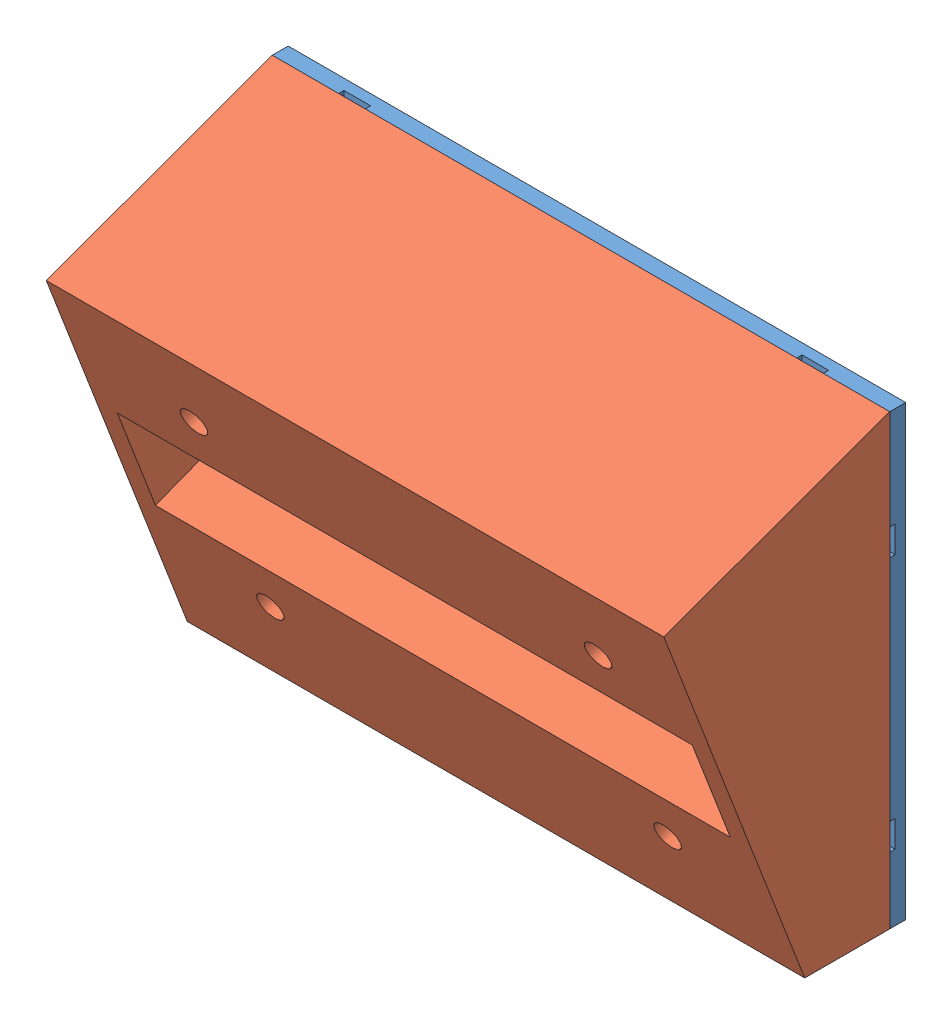
SolidWorks assembly front, configuration Default. Lengths in mm.
Overall size (116.2 84.29 45.53).
3 component instances, 3 part files, 8 mates.
Components (placement in the parent):
- LCD_mod-1: LCD_mod [Default] at (-40.4424 10.3291 10.6735) size (106.2 68 14) (hidden)
- front-case-1: front-case [Default] at (-40.4424 10.3291 7.3235) x (-1 0 0) z (0 0 -1) size (116.2 84.29 10)
- bottom-1: bottom [Default] at (-40.4424 10.3291 7.3235) size (116.2 84.29 42.53)
Mates (geometry in assembly coordinates):
- InPlace1: in place: plane of LCD_mod-1 through (-100.5567 53.2526 7.3235) normal (0 0 -1); plane of ? through (0 0 7.3235) normal (0 0 -1); moOrthogonalPlaneRef_w of LCD_mod-1 through (-100.5567 53.2526 7.3235) normal (0 0 -1); plane of ? through (0 0 7.3235) normal (0 1 0); plane of LCD_mod-1 through (-100.5567 53.2526 7.3235) normal (0 0 -1); plane of ? through (0 0 7.3235) normal (-1 0 0); plane of LCD_mod-1 through (-100.5567 53.2526 7.3235) normal (0 0 -1); unknown of front-case-1
- Coincident1: coincident aligned: plane of LCD_mod-1; plane of front-case-1
- Coincident2: coincident aligned: moOrthogonalPlaneRef_w of LCD_mod-1 through (-40.4424 10.3291 7.3235) normal (0 1 0); plane of front-case-1 through (-40.4424 10.3291 7.3235) normal (0 1 0)
- Coincident3: coincident anti-aligned: moOrthogonalPlaneRef_w of LCD_mod-1 through (-40.4424 10.3291 7.3235) normal (1 0 0); plane of front-case-1 through (-40.4424 10.3291 7.3235) normal (-1 0 0)
- InPlace2: in place: plane of front-case-1 through (-40.4424 10.3291 7.3235) normal (0 0 1); plane of ? through (0 0 7.3235) normal (0 0 1); plane of front-case-1 through (-40.4424 10.3291 7.3235) normal (0 0 1); plane of ? through (0 0 7.3235) normal (0 1 0); plane of front-case-1 through (-40.4424 10.3291 7.3235) normal (0 0 1); plane of ? through (0 0 7.3235) normal (1 0 0); plane of front-case-1 through (-40.4424 10.3291 7.3235) normal (0 0 1); unknown of bottom-1
- Coincident4: coincident aligned: plane of front-case-1; plane of bottom-1
- Coincident5: coincident aligned: moOrthogonalPlaneRef_w of front-case-1 through (-40.4424 10.3291 7.3235) normal (0 1 0); plane of bottom-1 through (-40.4424 10.3291 7.3235) normal (0 1 0)
- Coincident6: coincident anti-aligned: moOrthogonalPlaneRef_w of front-case-1 through (-40.4424 10.3291 7.3235) normal (-1 0 0); plane of bottom-1 through (-40.4424 10.3291 7.3235) normal (1 0 0)
